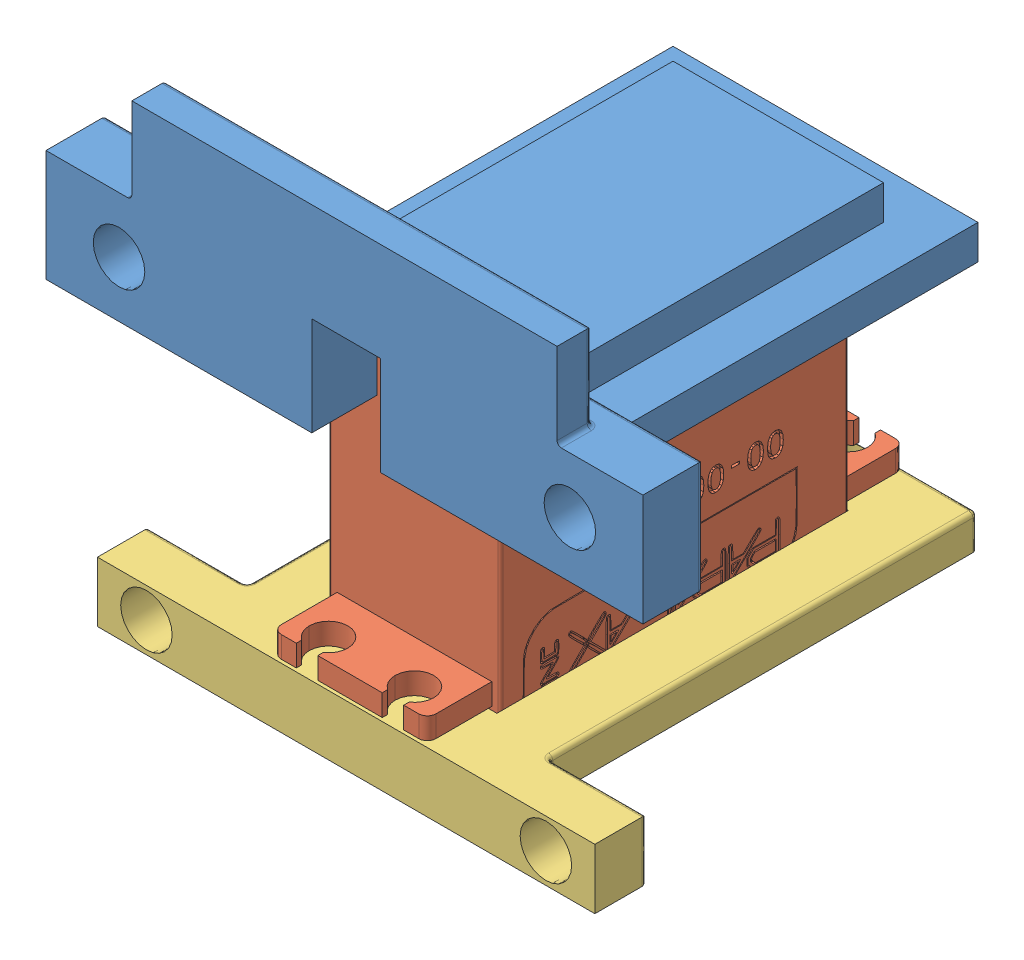
SolidWorks assembly bras retourneur sans bras, configuration Défaut. Lengths in mm.
Overall size (69.48 68.28 56).
3 component instances, 3 part files, 6 mates.
Components (placement in the parent):
- soutien-servo-fond M4 INSERT BIEN-1: soutien-servo-fond M4 INSERT BIEN [Défaut] at (9.3033 -10.6738 68.9819) size (69.48 23 56)
- Parallax Servo 900-00005-1: Parallax Servo 900-00005 [Défaut] at (3.2033 -6.6738 48.9819) x (1 0 0) z (0 -1 0) size (20.01 55.5 42.1)
- soutien-servo M4 INSERT BIEN-1: soutien-servo M4 INSERT BIEN [Défaut] at (-3.2967 -35.7738 68.8819) x (-1 0 0) z (0 0 1) size (57.9 20.18 55.9)
Mates (geometry in assembly coordinates):
- Coïncidente1: coincident: plane of soutien-servo-fond M4 INSERT BIEN-1 through (9.3033 -6.6738 68.9819) normal (0 -1 0); plane of Parallax Servo 900-00005-1 through (3.2033 -6.6738 48.9819) normal (0 1 0)
- Coïncidente2: coincident: plane of soutien-servo-fond M4 INSERT BIEN-1 through (-6.7967 -6.6738 68.9819) normal (1 0 0); plane of Parallax Servo 900-00005-1 through (-6.7967 -6.6738 48.9819) normal (-1 0 0)
- Coïncidente3: coincident anti-aligned: plane of soutien-servo-fond M4 INSERT BIEN-1 through (9.3033 -6.6738 48.9819) normal (0 0 1); plane of Parallax Servo 900-00005-1 through (3.2033 -42.7738 48.9819) normal (0 0 -1)
- Coïncidente4: coincident: plane of Parallax Servo 900-00005-1 through (3.2033 -35.7738 48.9819) normal (0 -1 0); plane of soutien-servo M4 INSERT BIEN-1 through (-3.2967 -35.7738 68.8819) normal (0 1 0)
- Coïncidente5: coincident: plane of Parallax Servo 900-00005-1 through (13.2033 -6.6738 48.9819) normal (1 0 0); plane of soutien-servo M4 INSERT BIEN-1 through (13.2033 -39.7738 48.9819) normal (-1 0 0)
- Coïncidente6: coincident anti-aligned: plane of Parallax Servo 900-00005-1 through (3.2033 -42.7738 48.9819) normal (0 0 -1); plane of soutien-servo M4 INSERT BIEN-1 through (-6.8967 -39.7738 48.9819) normal (0 0 1)
